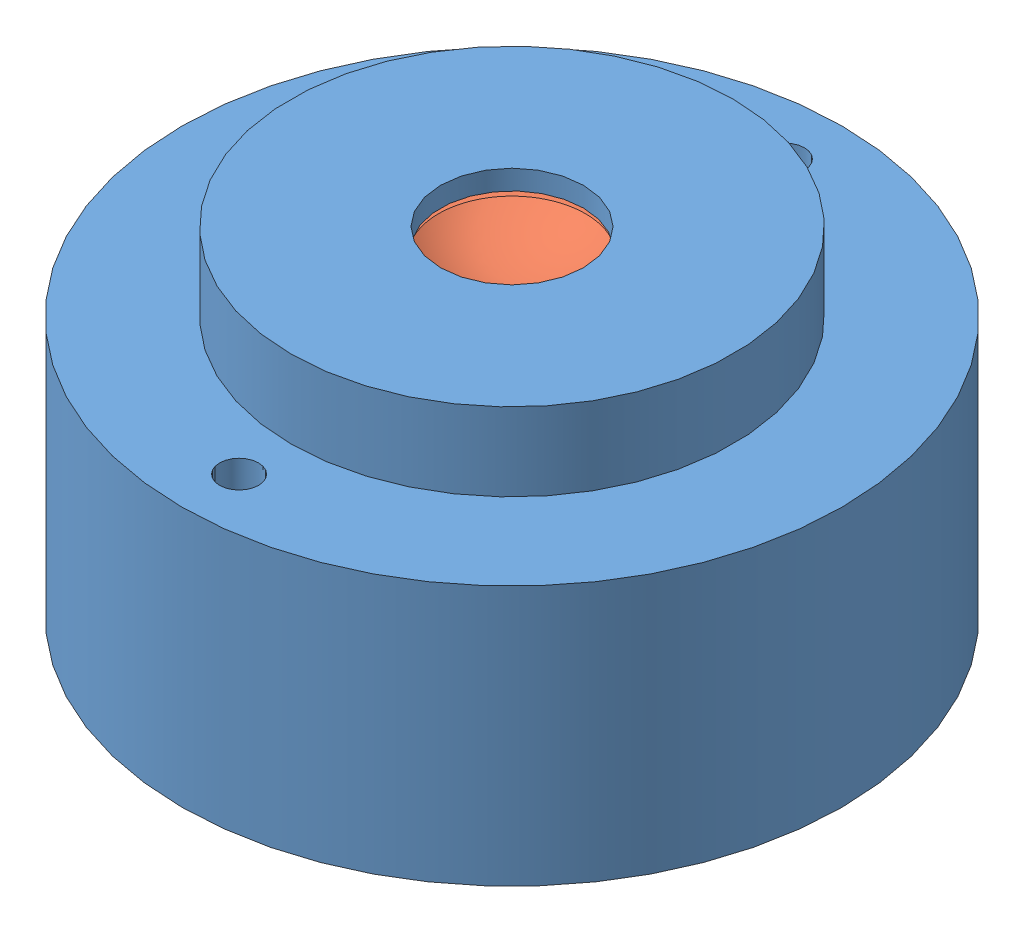
SolidWorks assembly negative lens subassembly, configuration Default. Lengths in mm.
Overall size (25.4 13 25.4).
5 component instances, 4 part files, 4 mates.
Components (placement in the parent):
- negative lens holder-1: negative lens holder [Default] at (11.7973 9.277 20.9772) size (25.4 13 25.4)
- step_62472-1: step_62472 [Default] at (11.7973 20.3087 20.9772) x (-0.336076 0 -0.941835) z (0 -1 0) size (6.38 6.34 5.81)
  - NONE-1: NONE [Default] at origin size (6.35 6.34 5.02)
  - NONE_2-1: NONE_2 [Default] at origin size (6.35 6.34 3)
- negative lens retainer-1: negative lens retainer [Default] at (11.7973 16.3087 20.9772) x (0.375021 0 -0.927016) z (0 -1 0) size (6.3 6.24 7)
Mates (geometry in assembly coordinates):
- Concentric1: concentric aligned: cylinder of negative lens holder-1 through (11.7973 9.277 20.9772) axis (0 -1 0) radius 3.15; cylinder of step_62472-1/NONE-1 through (11.7973 21.292 20.9772) axis (0 -1 0) radius 3.125
- Coincident1: coincident anti-aligned: cone of negative lens holder-1 through (11.7973 21.277 20.9772) axis (0 1 0); circle of step_62472-1/NONE-1
- Concentric2: concentric anti-aligned: cylinder of negative lens holder-1 through (11.7973 9.277 20.9772) axis (0 -1 0) radius 3.15; cylinder of negative lens retainer-1 through (11.7973 9.3087 20.9772) axis (0 1 0) radius 3.15
- Coincident2: coincident anti-aligned: plane of step_62472-1/NONE_2-1 through (17.9936 16.3087 18.7661) normal (0 -1 0); plane of negative lens retainer-1 through (11.7973 16.3087 20.9772) normal (0 1 0)
